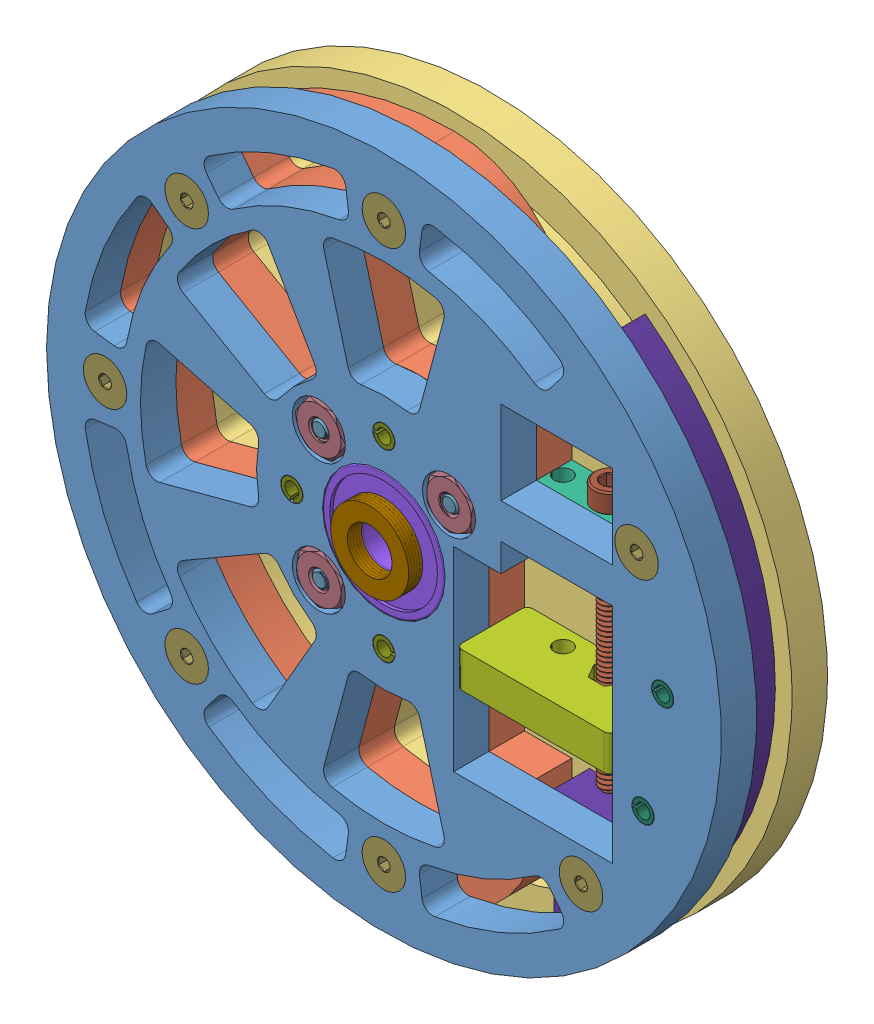
SolidWorks assembly A_4_000, configuration Default. Lengths in mm.
Overall size (121 121 36.85).
47 component instances, 17 part files, 66 mates.
Components (placement in the parent):
- A_4_001-1: A_4_001 [Default] at (3.3846 63.9451 111.2064) size (121 121 6.35)
- A_4_002-1: A_4_002 [Default] at (3.3846 63.9451 104.8564) size (78.5 115 6.35)
- A_4_004-1: A_4_004 [Default] at (3.3846 63.9451 98.5064) size (121 121 6.35)
- A_4_005-1: A_4_005 [Default] at (3.3846 63.9451 92.1564) size (40 40 6.35)
- A_4_006-1: A_4_006 [Default] at (3.3846 63.9451 85.8064) size (45 45 6.35)
- A_4_007-1: A_4_007 [Default] at (20.8846 80.9451 104.8564) x (1 0 0) z (0 -1 0) size (27 6.35 6.35)
- A_4_008-2: A_4_008 [Default] at (43.8846 47.961 104.8564) x (-1 0 0) z (0 0 -1) size (27.5 6.35 12.7)
- 110300107560_B608ZZ-1: 110300107560_B608ZZ [Default] at (3.3846 63.9451 110.6064) x (0 0 1) z (-1 0 0) size (7 22 22)
- 110300107560_B608ZZ-2: 110300107560_B608ZZ [Default] at (3.3846 63.9451 85.7564) x (0 0 1) z (-0.634605 0.772837 0) size (7 22 22)
- 98055A114-8: 98055A114 [Default] at (3.3846 63.9451 85.2564) x (0.998288 0.058487 0) z (0 0 1) size (14 14 0.5)
- 98055A114-9: 98055A114 [Default] at (3.3846 63.9451 117.6064) x (0.968762 -0.24799 0) z (0 0 1) size (14 14 0.5)
- 98055A114-7: 98055A114 [Default] at (3.3846 63.9451 119.6064) x (0.994065 0.108791 0) z (0 0 1) size (14 14 0.5)
- 98055A114-10: 98055A114 [Default] at (3.3846 63.9451 84.7564) x (-0.013398 -0.99991 0) z (0 0 1) size (14 14 0.5)
- 98055A114-19: 98055A114 [Default] at (3.3846 63.9451 118.1064) x (0.906228 -0.42279 0) z (0 0 1) size (14 14 0.5)
- 98055A114-17: 98055A114 [Default] at (3.3846 63.9451 118.6064) x (0.9988 -0.048984 0) z (0 0 1) size (14 14 0.5)
- 98055A114-16: 98055A114 [Default] at (3.3846 63.9451 119.1064) x (0.998907 -0.046732 0) z (0 0 1) size (14 14 0.5)
- 98055A114-18: 98055A114 [Default] at (3.3846 63.9451 84.2564) x (0.793844 0.608122 0) z (0 0 1) size (14 14 0.5)
- 98055A114-20: 98055A114 [Default] at (3.3846 63.9451 83.7564) x (0.962009 0.273018 0) z (0 0 1) size (14 14 0.5)
- 98055A114-15: 98055A114 [Default] at (3.3846 63.9451 83.2564) x (0.99888 -0.047305 0) z (0 0 1) size (14 14 0.5)
- 98892A200-1: 98892A200 [98892A200] at (34.3846 48.9595 108.0314) x (0.866025 0 -0.5) z (0 1 0) size (6.2 6.2 3.77)
- 92196A168-1: 92196A168 [92196A168] at (34.3846 36.4951 108.0314) x (1 0 0) z (0 -1 0) size (5.74 5.74 48.6)
- 92210A151-8: 92210A151 [92210A151] at (3.3846 113.9451 117.5564) size (7.8 7.8 19.48)
- 95170A355-1: 95170A355 [95170A355] at (3.3846 113.9451 102.0783) x (-0.797791 -0.602935 0) z (0.602935 -0.797791 0) size (8.33 3.94 9.17)
- 92210A151-7: 92210A151 [92210A151] at (48.7 85.076 117.5564) size (7.8 7.8 19.48)
- 95170A355-7: 95170A355 [95170A355] at (48.7 85.076 102.0783) x (-0.923728 -0.383049 0) z (0.383049 -0.923728 0) size (8.33 3.94 9.17)
- 92210A155-1: 92210A155 [92210A155] at (15.0519 75.6123 85.8064) x (-1 0 0) z (0 0 -1) size (7.8 7.8 32.26)
- 95170A355-8: 95170A355 [95170A355] at (15.0519 75.6123 113.9845) x (-0.996666 0.081588 0) z (0.081588 0.996666 0) size (8.33 3.94 9.17)
- 92373A215-3: 92373A215 [92373A215] at (53.3634 65.3993 108.0314) size (4.08 4.11 19.05)
- 92373A215-2: 92373A215 [92373A215] at (49.852 45.4848 108.0314) size (4.08 4.11 19.05)
- 92373A218-1: 92373A218 [92373A218] at (3.3846 80.4451 101.6814) size (4.08 4.11 31.75)
- 95170A355-2: 95170A355 [95170A355] at (38.7399 28.5897 102.0783) x (0.137784 0.990462 0) z (-0.990462 0.137784 0) size (8.33 3.94 9.17)
- 95170A355-3: 95170A355 [95170A355] at (3.3846 13.9451 102.0783) x (0.797791 0.602935 0) z (-0.602935 0.797791 0) size (8.33 3.94 9.17)
- 95170A355-4: 95170A355 [95170A355] at (-31.9707 28.5897 102.0783) x (0.990462 -0.137784 0) z (0.137784 0.990462 0) size (8.33 3.94 9.17)
- 95170A355-5: 95170A355 [95170A355] at (-46.6154 63.9451 102.0783) x (0.602935 -0.797791 0) z (0.797791 0.602935 0) size (8.33 3.94 9.17)
- 95170A355-6: 95170A355 [95170A355] at (-31.9707 99.3004 102.0783) x (-0.137784 -0.990462 0) z (0.990462 -0.137784 0) size (8.33 3.94 9.17)
- 92210A151-9: 92210A151 [92210A151] at (38.7399 28.5897 117.5564) x (-0.707107 -0.707107 0) z (0 0 1) size (7.8 7.8 19.48)
- 92210A151-10: 92210A151 [92210A151] at (3.3846 13.9451 117.5564) x (-1 0 0) z (0 0 1) size (7.8 7.8 19.48)
- 92210A151-11: 92210A151 [92210A151] at (-31.9707 28.5897 117.5564) x (-0.707107 0.707107 0) z (0 0 1) size (7.8 7.8 19.48)
- 92210A151-12: 92210A151 [92210A151] at (-46.6154 63.9451 117.5564) x (0 1 0) z (0 0 1) size (7.8 7.8 19.48)
- 92210A151-13: 92210A151 [92210A151] at (-31.9707 99.3004 117.5564) x (0.707107 0.707107 0) z (0 0 1) size (7.8 7.8 19.48)
- 92210A155-2: 92210A155 [92210A155] at (-8.2827 52.2778 85.8064) x (1 0 0) z (0 0 -1) size (7.8 7.8 32.26)
- 92210A155-3: 92210A155 [92210A155] at (-8.2827 75.6123 85.8064) x (0 -1 0) z (0 0 -1) size (7.8 7.8 32.26)
- 95170A355-9: 95170A355 [95170A355] at (-8.2827 52.2778 113.9845) x (0.996666 -0.081588 0) z (-0.081588 -0.996666 0) size (8.33 3.94 9.17)
- 95170A355-10: 95170A355 [95170A355] at (-8.2827 75.6123 113.9845) x (-0.081588 -0.996666 0) z (-0.996666 0.081588 0) size (8.33 3.94 9.17)
- 92373A218-2: 92373A218 [92373A218] at (3.3846 47.4451 101.6814) x (-1 0 0) z (0 0 1) size (4.08 4.11 31.75)
- 92373A218-3: 92373A218 [92373A218] at (-13.1154 63.9451 101.6814) x (0 1 0) z (0 0 1) size (4.08 4.11 31.75)
- A_4_003-1: A_4_003 [Default] at (3.3846 63.9451 104.8564) size (33.33 98.41 6.35)
Mates (geometry in assembly coordinates):
- Concentric1: concentric aligned: cylinder of A_4_001-1 through (3.3846 63.9451 117.5564) axis (0 0 -1) radius 11; cylinder of A_4_002-1 through (3.3846 63.9451 111.2064) axis (0 0 -1) radius 8
- Concentric2: concentric aligned: cylinder of A_4_001-1 through (3.3846 113.9451 117.5564) axis (0 0 -1) radius 1.8986; cylinder of A_4_002-1 through (3.3846 113.9451 111.2064) axis (0 0 -1) radius 1.8986
- Coincident1: coincident anti-aligned: plane of A_4_001-1 through (3.3846 63.9451 111.2064) normal (0 0 -1); plane of A_4_002-1 through (3.3846 63.9451 111.2064) normal (0 0 1)
- Concentric3: concentric aligned: cylinder of A_4_001-1 through (3.3846 63.9451 117.5564) axis (0 0 -1) radius 11; cylinder of A_4_004-1 through (3.3846 63.9451 104.8564) axis (0 0 -1) radius 8
- Concentric4: concentric aligned: cylinder of A_4_001-1 through (3.3846 80.4451 117.5564) axis (0 0 -1) radius 1.9939; cylinder of A_4_004-1 through (3.3846 80.4451 104.8564) axis (0 0 -1) radius 1.9939
- Coincident2: coincident anti-aligned: plane of A_4_002-1 through (3.3846 63.9451 104.8564) normal (0 0 -1); plane of A_4_004-1 through (3.3846 63.9451 104.8564) normal (0 0 1)
- Concentric5: concentric aligned: cylinder of A_4_001-1 through (3.3846 63.9451 117.5564) axis (0 0 -1) radius 11; cylinder of A_4_005-1 through (3.3846 63.9451 98.5064) axis (0 0 -1) radius 8
- Concentric6: concentric aligned: cylinder of A_4_001-1 through (3.3846 80.4451 117.5564) axis (0 0 -1) radius 1.9939; cylinder of A_4_005-1 through (3.3846 80.4451 98.5064) axis (0 0 -1) radius 1.9939
- Concentric7: concentric aligned: cylinder of A_4_005-1 through (3.3846 63.9451 98.5064) axis (0 0 -1) radius 8; cylinder of A_4_006-1 through (3.3846 63.9451 92.1564) axis (0 0 -1) radius 11
- Concentric8: concentric aligned: cylinder of A_4_005-1 through (3.3846 80.4451 98.5064) axis (0 0 -1) radius 1.9939; cylinder of A_4_006-1 through (3.3846 80.4451 92.1564) axis (0 0 -1) radius 1.9939
- Coincident4: coincident anti-aligned: plane of A_4_005-1 through (3.3846 63.9451 92.1564) normal (0 0 -1); plane of A_4_006-1 through (3.3846 63.9451 92.1564) normal (0 0 1)
- Concentric9: concentric anti-aligned: cylinder of A_4_001-1 through (3.3846 63.9451 117.5564) axis (0 0 -1) radius 11; cylinder of 110300107560_B608ZZ-1 through (3.3846 63.9451 110.6036) axis (0 0 1) radius 4
- Coincident5: coincident aligned: plane of A_4_001-1 through (3.3846 63.9451 111.2064) normal (0 0 -1); plane of 110300107560_B608ZZ-1 through (3.3846 73.5951 111.2064) normal (0 0 -1)
- Concentric11: concentric anti-aligned: cylinder of A_4_006-1 through (3.3846 63.9451 92.1564) axis (0 0 -1) radius 11; cylinder of 110300107560_B608ZZ-2 through (3.3846 63.9451 85.7536) axis (0 0 1) radius 4
- Coincident8: coincident aligned: plane of A_4_006-1 through (3.3846 63.9451 92.1564) normal (0 0 1); plane of 110300107560_B608ZZ-2 through (8.0989 67.8162 92.1564) normal (0 0 1)
- Concentric13: concentric anti-aligned: cylinder of 110300107560_B608ZZ-2 through (3.3846 63.9451 85.7536) axis (0 0 1) radius 4; cylinder of 98055A114-8 through (3.3846 63.9451 85.7564) axis (0 0 -1) radius 4
- Concentric18: concentric anti-aligned: cylinder of 110300107560_B608ZZ-1 through (3.3846 63.9451 110.6036) axis (0 0 1) radius 4; cylinder of 98055A114-9 through (3.3846 63.9451 118.1064) axis (0 0 -1) radius 4
- Coincident15: coincident anti-aligned: plane of 110300107560_B608ZZ-1 through (3.3846 68.2451 117.6064) normal (0 0 1); plane of 98055A114-9 through (3.3846 63.9451 117.6064) normal (0 0 -1)
- Concentric19: concentric anti-aligned: cylinder of 110300107560_B608ZZ-1 through (3.3846 63.9451 110.6036) axis (0 0 1) radius 4; cylinder of 98055A114-7 through (3.3846 63.9451 120.1064) axis (0 0 -1) radius 4
- Coincident19: coincident anti-aligned: plane of 110300107560_B608ZZ-2 through (8.0989 67.8162 85.7564) normal (0 0 -1); plane of 98055A114-8 through (3.3846 63.9451 85.7564) normal (0 0 1)
- Coincident30: coincident anti-aligned: plane of A_4_004-1 through (3.3846 63.9451 104.8564) normal (0 0 1); plane of A_4_007-1 through (20.8846 74.5951 104.8564) normal (0 0 -1)
- Coincident31: coincident anti-aligned: plane of A_4_002-1 through (20.8846 74.5951 111.2064) normal (0 1 0); plane of A_4_007-1 through (20.8846 74.5951 111.2064) normal (0 -1 0)
- Concentric31: concentric aligned: cylinder of A_4_007-1 through (34.3846 74.5951 108.0314) axis (0 1 0) radius 2.16; circle of 98892A200-1
- Concentric32: concentric anti-aligned: cylinder of A_4_007-1 through (34.3846 74.5951 108.0314) axis (0 1 0) radius 2.16; circle of 92196A168-1
- Coincident43: coincident anti-aligned: plane of A_4_007-1 through (20.8846 80.9451 111.2064) normal (0 1 0); plane of 92196A168-1 through (34.3846 80.9451 108.0314) normal (0 -1 0)
- Coincident56: coincident anti-aligned: plane of A_4_004-1 through (3.3846 63.9451 104.8564) normal (0 0 1); plane of A_4_008-2 through (43.8846 54.311 104.8564) normal (0 0 -1)
- Concentric44: concentric anti-aligned: cylinder of A_4_007-1 through (25.9721 74.5951 108.0314) axis (0 1 0) radius 1.5875; cylinder of A_4_008-2 through (25.9721 54.311 108.0314) axis (0 -1 0) radius 1.5875
- Coincident57: coincident anti-aligned: plane of 98892A200-1 through (34.3846 47.961 108.0314) normal (0 1 0); plane of A_4_008-2 through (43.8846 47.961 104.8564) normal (0 -1 0)
- Concentric54: concentric anti-aligned: cylinder of 110300107560_B608ZZ-2 through (3.3846 63.9451 85.7536) axis (0 0 1) radius 4; cylinder of 98055A114-10 through (3.3846 63.9451 85.2564) axis (0 0 -1) radius 4
- Coincident68: coincident anti-aligned: plane of 98055A114-8 through (3.3846 63.9451 85.2564) normal (0 0 -1); plane of 98055A114-10 through (3.3846 63.9451 85.2564) normal (0 0 1)
- Coincident69: coincident anti-aligned: plane of A_4_004-1 through (3.3846 63.9451 98.5064) normal (0 0 -1); plane of A_4_005-1 through (3.3846 63.9451 98.5064) normal (0 0 1)
- Concentric55: concentric aligned: cylinder of A_4_001-1 through (3.3846 113.9451 117.5564) axis (0 0 -1) radius 1.8986; circle of 92210A151-8
- Coincident70: coincident aligned: plane of A_4_001-1 through (3.3846 63.9451 117.5564) normal (0 0 1); plane of 92210A151-8 through (3.3846 112.1925 117.5564) normal (0 0 1)
- Concentric56: concentric aligned: cylinder of A_4_004-1 through (3.3846 113.9451 102.0783) axis (0 0 -1) radius 4.7625; circle of 95170A355-1
- Coincident71: coincident anti-aligned: plane of A_4_004-1 through (3.3846 113.9451 102.0783) normal (0 0 -1); plane of 95170A355-1 through (0.6215 117.6011 102.0783) normal (0 0 1)
- Concentric57: concentric aligned: cylinder of A_4_001-1 through (48.7 85.076 117.5564) axis (0 0 -1) radius 1.8986; circle of 92210A151-7
- Coincident72: coincident aligned: plane of A_4_001-1 through (3.3846 63.9451 117.5564) normal (0 0 1); plane of 92210A151-7 through (48.7 83.3234 117.5564) normal (0 0 1)
- Concentric58: concentric aligned: cylinder of A_4_004-1 through (48.7 85.076 102.0783) axis (0 0 -1) radius 4.7625; circle of 95170A355-7
- Coincident73: coincident anti-aligned: plane of A_4_004-1 through (48.7 85.076 102.0783) normal (0 0 -1); plane of 95170A355-7 through (46.9446 89.3092 102.0783) normal (0 0 1)
- Concentric60: concentric anti-aligned: cylinder of A_4_006-1 through (15.0519 75.6123 92.1564) axis (0 0 -1) radius 1.8986; circle of 92210A155-1
- Coincident75: coincident aligned: plane of A_4_006-1 through (3.3846 63.9451 85.8064) normal (0 0 -1); plane of 92210A155-1 through (15.0519 75.6123 85.8064) normal (0 0 -1)
- Concentric61: concentric aligned: cylinder of A_4_001-1 through (15.0519 75.6123 113.9845) axis (0 0 1) radius 4.7625; circle of 95170A355-8
- Concentric62: concentric aligned: cylinder of A_4_001-1 through (53.3634 65.3993 117.5564) axis (0 0 -1) radius 1.9939; circle of 92373A215-3
- Coincident77: coincident aligned: plane of A_4_001-1 through (3.3846 63.9451 117.5564) normal (0 0 1); plane of 92373A215-3 through (53.3634 65.3993 117.5564) normal (0 0 1)
- Concentric63: concentric aligned: cylinder of A_4_001-1 through (49.852 45.4848 117.5564) axis (0 0 -1) radius 1.9939; circle of 92373A215-2
- Coincident78: coincident aligned: plane of A_4_001-1 through (3.3846 63.9451 117.5564) normal (0 0 1); plane of 92373A215-2 through (49.852 45.4848 117.5564) normal (0 0 1)
- Concentric64: concentric aligned: cylinder of A_4_001-1 through (3.3846 80.4451 117.5564) axis (0 0 -1) radius 1.9939; circle of 92373A218-1
- Coincident79: coincident aligned: plane of A_4_001-1 through (3.3846 63.9451 117.5564) normal (0 0 1); plane of 92373A218-1 through (3.3846 80.4451 117.5564) normal (0 0 1)
- Coincident80: coincident anti-aligned: plane of A_4_001-1 through (15.0519 75.6123 113.9845) normal (0 0 1); plane of 95170A355-8 through (14.678 71.0449 113.9845) normal (0 0 -1)
- Concentric65: concentric anti-aligned: cylinder of 110300107560_B608ZZ-1 through (3.3846 63.9451 110.6036) axis (0 0 1) radius 4; cylinder of 98055A114-19 through (3.3846 63.9451 118.6064) axis (0 0 -1) radius 4
- Coincident81: coincident anti-aligned: plane of 98055A114-9 through (3.3846 63.9451 118.1064) normal (0 0 1); plane of 98055A114-19 through (3.3846 63.9451 118.1064) normal (0 0 -1)
- Concentric66: concentric anti-aligned: cylinder of 110300107560_B608ZZ-1 through (3.3846 63.9451 110.6036) axis (0 0 1) radius 4; cylinder of 98055A114-17 through (3.3846 63.9451 119.1064) axis (0 0 -1) radius 4
- Coincident82: coincident anti-aligned: plane of 98055A114-19 through (3.3846 63.9451 118.6064) normal (0 0 1); plane of 98055A114-17 through (3.3846 63.9451 118.6064) normal (0 0 -1)
- Concentric67: concentric anti-aligned: cylinder of 110300107560_B608ZZ-1 through (3.3846 63.9451 110.6036) axis (0 0 1) radius 4; cylinder of 98055A114-16 through (3.3846 63.9451 119.6064) axis (0 0 -1) radius 4
- Coincident83: coincident anti-aligned: plane of 98055A114-17 through (3.3846 63.9451 119.1064) normal (0 0 1); plane of 98055A114-16 through (3.3846 63.9451 119.1064) normal (0 0 -1)
- Coincident84: coincident anti-aligned: plane of 98055A114-7 through (3.3846 63.9451 119.6064) normal (0 0 -1); plane of 98055A114-16 through (3.3846 63.9451 119.6064) normal (0 0 1)
- Concentric68: concentric anti-aligned: cylinder of 110300107560_B608ZZ-2 through (3.3846 63.9451 85.7536) axis (0 0 1) radius 4; cylinder of 98055A114-18 through (3.3846 63.9451 84.7564) axis (0 0 -1) radius 4
- Coincident85: coincident anti-aligned: plane of 98055A114-10 through (3.3846 63.9451 84.7564) normal (0 0 -1); plane of 98055A114-18 through (3.3846 63.9451 84.7564) normal (0 0 1)
- Concentric69: concentric anti-aligned: cylinder of 110300107560_B608ZZ-2 through (3.3846 63.9451 85.7536) axis (0 0 1) radius 4; cylinder of 98055A114-20 through (3.3846 63.9451 84.2564) axis (0 0 -1) radius 4
- Coincident86: coincident anti-aligned: plane of 98055A114-18 through (3.3846 63.9451 84.2564) normal (0 0 -1); plane of 98055A114-20 through (3.3846 63.9451 84.2564) normal (0 0 1)
- Concentric70: concentric anti-aligned: cylinder of 110300107560_B608ZZ-2 through (3.3846 63.9451 85.7536) axis (0 0 1) radius 4; cylinder of 98055A114-15 through (3.3846 63.9451 83.7564) axis (0 0 -1) radius 4
- Coincident87: coincident anti-aligned: plane of 98055A114-20 through (3.3846 63.9451 83.7564) normal (0 0 -1); plane of 98055A114-15 through (3.3846 63.9451 83.7564) normal (0 0 1)
- Coincident88: coincident anti-aligned: plane of A_4_002-1 through (20.8846 80.9451 111.2064) normal (1 0 0); plane of A_4_007-1 through (20.8846 74.5951 104.8564) normal (-1 0 0)
- Concentric71: concentric aligned: cylinder of A_4_001-1 through (38.7399 28.5897 117.5564) axis (0 0 -1) radius 1.8986; cylinder of A_4_003-1 through (38.7399 28.5897 111.2064) axis (0 0 -1) radius 1.8986
- Concentric72: concentric aligned: cylinder of A_4_001-1 through (48.7 85.076 117.5564) axis (0 0 -1) radius 1.8986; cylinder of A_4_003-1 through (48.7 85.076 111.2064) axis (0 0 -1) radius 1.8986
- Coincident89: coincident anti-aligned: plane of A_4_001-1 through (3.3846 63.9451 111.2064) normal (0 0 -1); plane of A_4_003-1 through (3.3846 63.9451 111.2064) normal (0 0 1)
